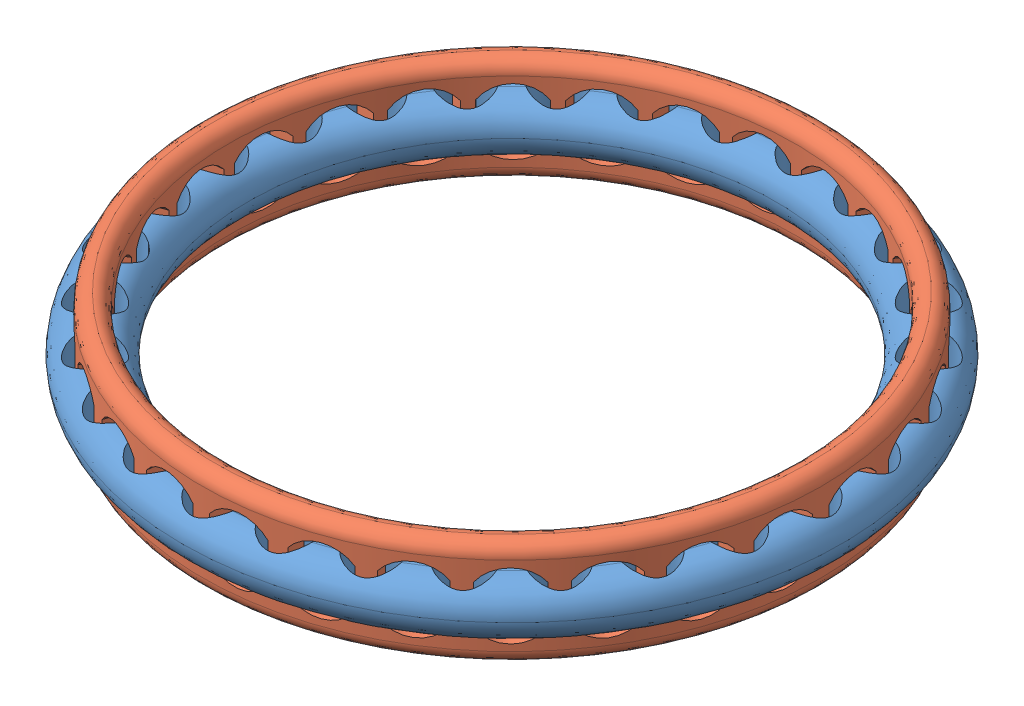
SolidWorks assembly ring, configuration Predeterminado. Lengths in mm.
Overall size (29.98 4 29.98).
2 component instances, 2 part files, 1 mates.
Components (placement in the parent):
- aro1-1: aro1 [Predeterminado] at origin size (25 2.12 25)
- aro2-1: aro2 [Predeterminado] at (0 1.022 0) x (0.332799 0 -0.942998) z (0.942998 0 0.332799) size (23.5 4 23.5)
Mates (geometry in assembly coordinates):
- Concéntrica1: concentric anti-aligned: circle of aro1-1; cylinder of aro2-1 through (0 -0.978 0) axis (0 1 0) radius 11.75
